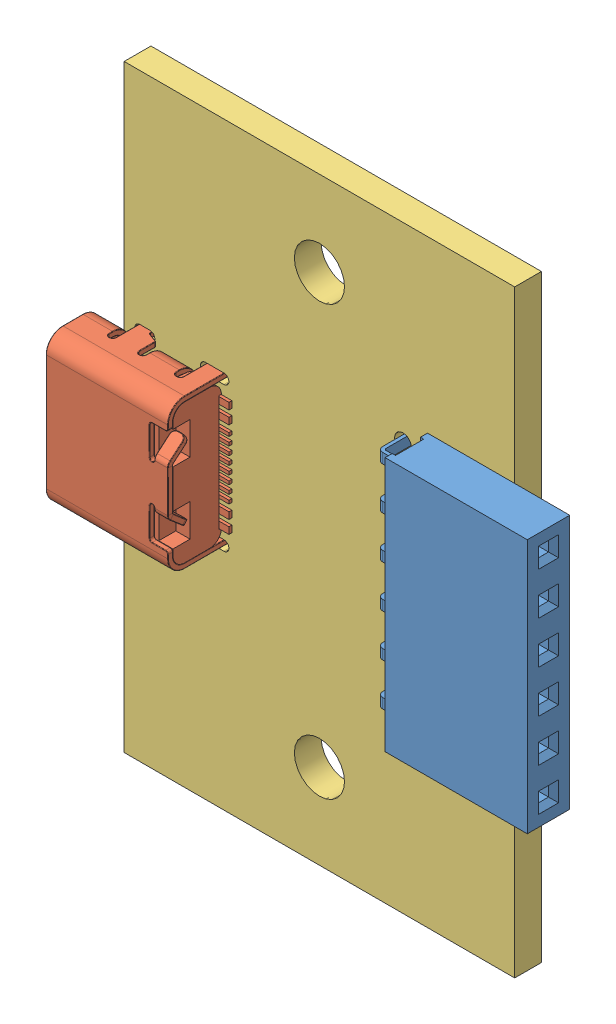
SolidWorks assembly Type-C_Ext, configuration 默认. Lengths in mm.
Overall size (28.17 35.81 6.47).
6 component instances, 3 part files, 0 mates.
Components (placement in the parent):
- Type-C_Ext(2)^Type-C_Ext-1: Type-C_Ext(2)^Type-C_Ext [默认] at origin size (28.17 35.81 6.47) (virtual)
  - PinSocket_1x06_P2.54mm_Horizontal^Type-C_Ext(2)_Type-C_Ext-1: PinSocket_1x06_P2.54mm_Horizontal^Type-C_Ext(2)_Type-C_Ext [默认] at (120.06 -95.733 1.65) x (-1 0 0) z (0 0 1) size (10.13 15.24 5.84) (virtual)
    - SOLID^PinSocket_1x06_P2.54mm_Horizontal_Type-C_Ext(2)_Type-C_Ext-1: SOLID^PinSocket_1x06_P2.54mm_Horizontal_Type-C_Ext(2)_Type-C_Ext [默认] at origin size (10.13 15.24 5.84) (virtual)
  - Type-C_16Pin_ThroughtHole^Type-C_Ext(2)_Type-C_Ext-1: Type-C_16Pin_ThroughtHole^Type-C_Ext(2)_Type-C_Ext [默认] at (106.934 -89.408 0.126) x (0 -1 0) z (0 0 1) size (8.94 7.9 4.1) (virtual)
    - COMPOUND^Type-C_16Pin_ThroughtHole_Type-C_Ext(2)_Type-C_Ext-1: COMPOUND^Type-C_16Pin_ThroughtHole_Type-C_Ext(2)_Type-C_Ext [默认] at origin size (8.94 7.9 4.1) (virtual)
  - Type-C_Ext PCB^Type-C_Ext(2)_Type-C_Ext-1: Type-C_Ext PCB^Type-C_Ext(2)_Type-C_Ext [默认] at origin size (23.37 35.81 1.6) (virtual)
